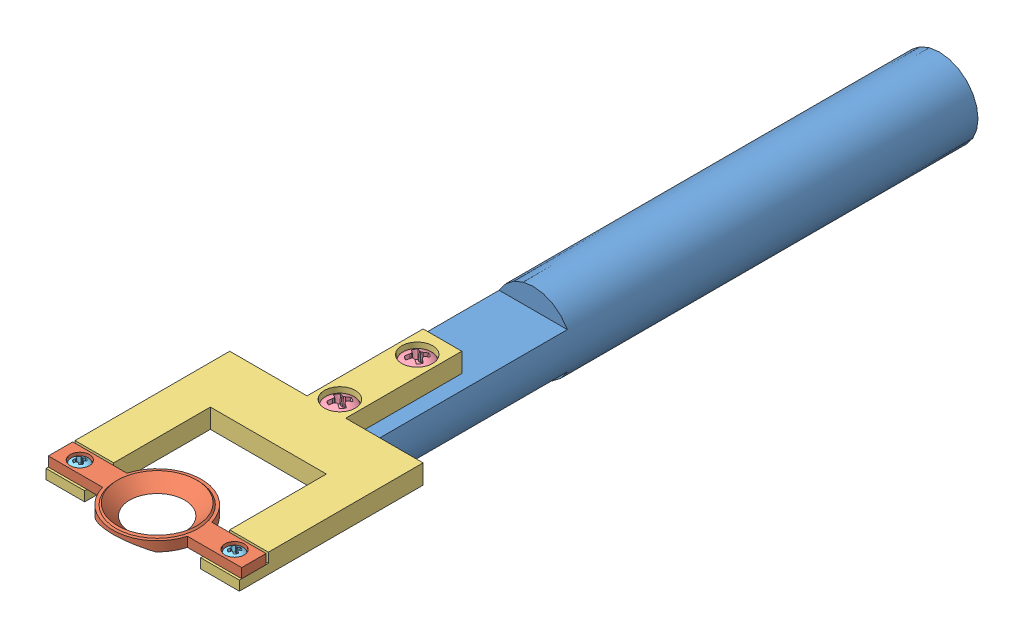
SolidWorks assembly 2_Photon_Microscopy_In_Vivo_Imaging_Fixture, configuration Default. Lengths in mm.
Overall size (31.75 14.58 135.67).
8 component instances, 6 part files, 17 mates.
Components (placement in the parent):
- Half_Pipe-1: Half_Pipe [Default] at (31.5449 53.942 80.7271) size (12.7 12.7 101.6)
- Work_Plate_Optical_Window-1: Work_Plate_Optical_Window [Default] at (31.5449 59.3232 158.3461) x (-1 0 0) z (0 0 -1) size (31.75 2.12 14.5)
- Head_Plate_Fork-1: Head_Plate_Fork [Default] at (31.5449 58.5295 145.6461) size (31.75 3.64 49.21)
- 91772A092_18-8 SS PAN HEAD PHILLIPS MACHINE SCREW-1: 91772A092_18-8 SS PAN HEAD PHILLIPS MACHINE SCREW [91772A092] at (31.5449 51.989 128.3521) x (-0.856074 0 -0.516853) z (0 1 0) size (4.9 4.9 8.38)
- 91772A092_18-8 SS PAN HEAD PHILLIPS MACHINE SCREW-2: 91772A092_18-8 SS PAN HEAD PHILLIPS MACHINE SCREW [91772A092] at (31.5449 51.989 115.6521) x (-0.837169 0 -0.546944) z (0 1 0) size (4.9 4.9 8.38)
- 91772A052_18-8 SS PAN HEAD PHILLIPS MACHINE SCREW-3: 91772A052_18-8 SS PAN HEAD PHILLIPS MACHINE SCREW [91772A052] at (18.8449 55.926 158.3461) x (-0.837169 0 -0.546944) z (0 1 0) size (2.95 2.95 6.38)
- 91772A052_18-8 SS PAN HEAD PHILLIPS MACHINE SCREW-4: 91772A052_18-8 SS PAN HEAD PHILLIPS MACHINE SCREW [91772A052] at (44.2449 55.926 158.3461) x (-0.837169 0 -0.546944) z (0 1 0) size (2.95 2.95 6.38)
- Objective Blocker-1: Objective Blocker [Default] at (31.5449 75.1361 158.3461) x (0.837913 0 -0.545804) z (0.545804 0 0.837913) size (42.4 35.5 42.4) (hidden)
Mates (geometry in assembly coordinates):
- Parallel1: parallel: plane of Half_Pipe-1 through (31.5449 53.942 96.6021) normal (0 0 1); plane of Head_Plate_Fork-1 through (28.3699 60.117 111.5148) normal (0 0 -1)
- Coincident3: coincident: plane of Half_Pipe-1 through (31.5449 56.942 96.6021) normal (0 1 0); plane of Head_Plate_Fork-1 through (31.5449 56.942 145.6461) normal (0 -1 0)
- Coincident4: coincident: plane of Work_Plate_Optical_Window-1 through (31.5449 58.5295 158.3461) normal (0 -1 0); plane of Head_Plate_Fork-1 through (31.5449 58.5295 145.6461) normal (0 1 0)
- Concentric26: concentric: circle of Head_Plate_Fork-1; line of ? through (18.8449 55.926 158.3461) axis (0 1 0)
- Concentric27: concentric: circle of Work_Plate_Optical_Window-1; circle of Head_Plate_Fork-1
- Concentric30: concentric: circle of Work_Plate_Optical_Window-1; circle of Head_Plate_Fork-1
- Concentric35: concentric: cylinder of Work_Plate_Optical_Window-1 through (18.8449 59.101 158.3461) axis (0 1 0) radius 1.5875; line of 91772A052_18-8 SS PAN HEAD PHILLIPS MACHINE SCREW-3 through (18.8449 55.926 158.3461) axis (0 1 0)
- Coincident43: coincident: plane of Work_Plate_Optical_Window-1 through (18.8449 59.101 158.3461) normal (0 1 0); plane of 91772A052_18-8 SS PAN HEAD PHILLIPS MACHINE SCREW-3 through (18.8449 59.101 158.3461) normal (0 -1 0)
- Concentric36: concentric: cylinder of Work_Plate_Optical_Window-1 through (44.2449 59.101 158.3461) axis (0 1 0) radius 1.5875; line of 91772A052_18-8 SS PAN HEAD PHILLIPS MACHINE SCREW-4 through (44.2449 55.926 158.3461) axis (0 1 0)
- Coincident45: coincident: plane of Work_Plate_Optical_Window-1 through (44.2449 59.101 158.3461) normal (0 1 0); plane of 91772A052_18-8 SS PAN HEAD PHILLIPS MACHINE SCREW-4 through (44.2449 59.101 158.3461) normal (0 -1 0)
- Concentric37: concentric: cylinder of Head_Plate_Fork-1 through (31.5449 58.339 128.3521) axis (0 1 0) radius 2.54; line of 91772A092_18-8 SS PAN HEAD PHILLIPS MACHINE SCREW-1 through (31.5449 51.989 128.3521) axis (0 1 0)
- Concentric38: concentric: circle of Half_Pipe-1; cylinder of Head_Plate_Fork-1 through (31.5449 58.339 128.3521) axis (0 1 0) radius 2.54
- Coincident48: coincident: plane of Head_Plate_Fork-1 through (31.5449 58.339 128.3521) normal (0 1 0); plane of 91772A092_18-8 SS PAN HEAD PHILLIPS MACHINE SCREW-1 through (31.5449 58.339 128.3521) normal (0 -1 0)
- Concentric39: concentric: cylinder of Head_Plate_Fork-1 through (31.5449 58.339 115.6521) axis (0 1 0) radius 2.54; line of 91772A092_18-8 SS PAN HEAD PHILLIPS MACHINE SCREW-2 through (31.5449 51.989 115.6521) axis (0 1 0)
- Coincident50: coincident: plane of Head_Plate_Fork-1 through (31.5449 58.339 115.6521) normal (0 1 0); plane of 91772A092_18-8 SS PAN HEAD PHILLIPS MACHINE SCREW-2 through (31.5449 58.339 115.6521) normal (0 -1 0)
- Concentric40: concentric: circle of Work_Plate_Optical_Window-1; circle of Objective Blocker-1
- Coincident53: coincident: cone of Work_Plate_Optical_Window-1 through (31.5449 60.3738 158.3461) axis (0 -1 0); circle of Objective Blocker-1
